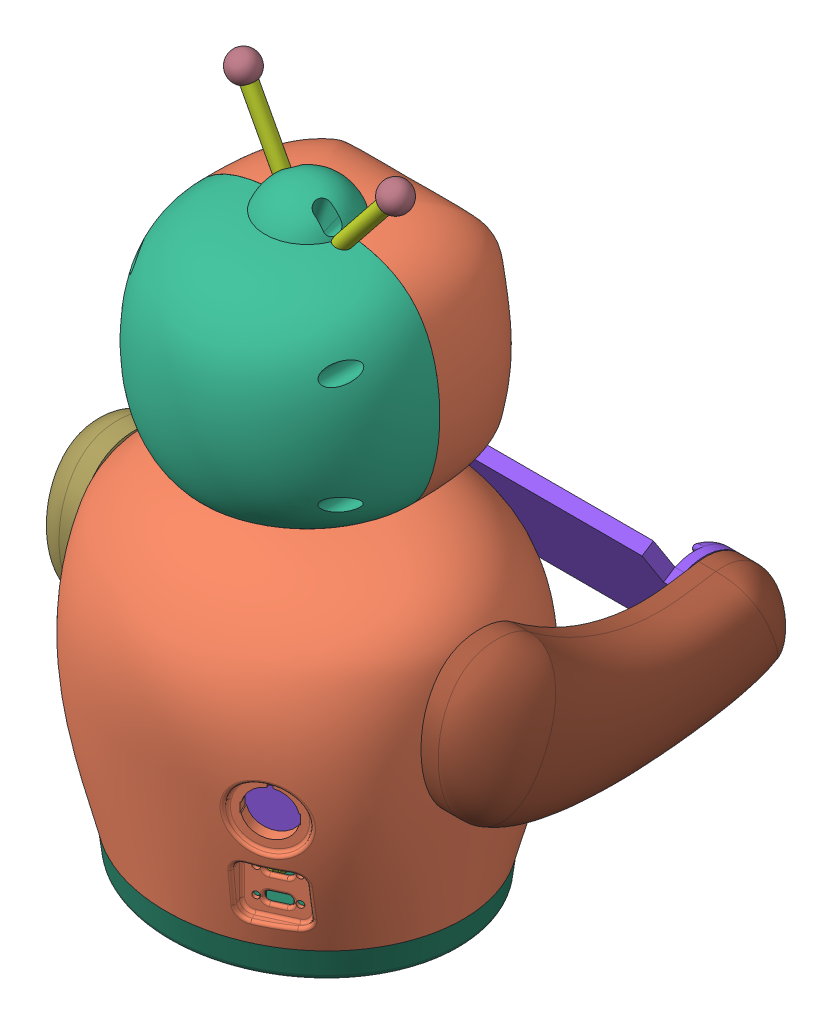
SolidWorks assembly hapi_assy, configuration Default. Lengths in mm.
Overall size (629.53 401.15 572.49).
108 component instances, 33 part files, 30 mates.
Components (placement in the parent):
- body_top_assy-1: body_top_assy [Default] at origin size (658.15 255.79 373.04)
  - body_top_with_inserts-1: body_top_with_inserts [Default] at origin size (206.75 213.33 145.9)
    - 93365A120_HEAT-SET INSERTS FOR PLASTICS-1: 93365A120_HEAT-SET INSERTS FOR PLASTICS [93365A120] at (-21.362 141.4958 103.8173) size (4.37 3.82 4.37)
    - 93365A120_HEAT-SET INSERTS FOR PLASTICS-9: 93365A120_HEAT-SET INSERTS FOR PLASTICS [93365A120] at (23.9683 141.4958 103.8173) size (4.37 3.82 4.37)
    - 93365A120_HEAT-SET INSERTS FOR PLASTICS-2: 93365A120_HEAT-SET INSERTS FOR PLASTICS [93365A120] at (-76.1668 95.7767 127.6298) x (0 1 0) z (0 0 1) size (4.37 3.82 4.37)
    - 93365A120_HEAT-SET INSERTS FOR PLASTICS-3: 93365A120_HEAT-SET INSERTS FOR PLASTICS [93365A120] at (-76.1668 75.4567 127.6298) x (0 1 0) z (0 0 1) size (4.37 3.82 4.37)
    - 93365A120_HEAT-SET INSERTS FOR PLASTICS-4: 93365A120_HEAT-SET INSERTS FOR PLASTICS [93365A120] at (-76.1668 75.4567 94.6098) x (0 1 0) z (0 0 1) size (4.37 3.82 4.37)
    - 93365A120_HEAT-SET INSERTS FOR PLASTICS-7: 93365A120_HEAT-SET INSERTS FOR PLASTICS [93365A120] at (-76.1668 95.7774 94.6098) x (0 0.999823 -0.018835) z (0 0.018835 0.999823) size (4.37 3.82 4.37)
    - 93365A120_HEAT-SET INSERTS FOR PLASTICS-5: 93365A120_HEAT-SET INSERTS FOR PLASTICS [93365A120] at (78.7732 75.4567 94.6098) x (0 -1 0) z (0 0 1) size (4.37 3.82 4.37)
    - 93365A120_HEAT-SET INSERTS FOR PLASTICS-6: 93365A120_HEAT-SET INSERTS FOR PLASTICS [93365A120] at (78.7732 95.7767 94.6098) x (0 -0.078661 -0.996901) z (0 -0.996901 0.078661) size (4.37 3.82 4.37)
    - 93365A120_HEAT-SET INSERTS FOR PLASTICS-11: 93365A120_HEAT-SET INSERTS FOR PLASTICS [93365A120] at (78.7732 95.7767 127.6298) x (0 0.381849 -0.924225) z (0 -0.924225 -0.381849) size (4.37 3.82 4.37)
    - 93365A120_HEAT-SET INSERTS FOR PLASTICS-8: 93365A120_HEAT-SET INSERTS FOR PLASTICS [93365A120] at (78.7732 75.4567 127.6298) x (0 0.381849 -0.924225) z (0 -0.924225 -0.381849) size (4.37 3.82 4.37)
    - 93365A120_HEAT-SET INSERTS FOR PLASTICS-10: 93365A120_HEAT-SET INSERTS FOR PLASTICS [93365A120] at (1.3032 4.3358 165.2218) x (-0.837169 0 -0.546944) z (-0.546944 0 0.837169) size (4.37 3.82 4.37)
    - 93365A120_HEAT-SET INSERTS FOR PLASTICS-12: 93365A120_HEAT-SET INSERTS FOR PLASTICS [93365A120] at (1.3032 4.3358 57.0178) x (-0.837169 0 -0.546944) z (-0.546944 0 0.837169) size (4.37 3.82 4.37)
    - 93365A120_HEAT-SET INSERTS FOR PLASTICS-13: 93365A120_HEAT-SET INSERTS FOR PLASTICS [93365A120] at (-59.1488 4.3358 111.1198) x (-0.837169 0 -0.546944) z (-0.546944 0 0.837169) size (4.37 3.82 4.37)
    - body_top-1: body_top [Default] at (1.3032 1.7958 111.1198) x (-1 0 0) z (0 0 1) size (162.51 139.72 145.9)
  - servomotor-1: servomotor [Predeterminado] at (61.1232 86.3965 111.1198) x (0 1 0) z (0 0 -1) size (53.82 44.84 19.95)
  - arm_base_right_assy-1: arm_base_right_assy [Default] at origin size (122.68 69.3 143.51)
    - 5862K103_HIGH-PULL RARE EARTH MAGNETIC DISC-1: 5862K103_HIGH-PULL RARE EARTH MAGNETIC DISC [5862K103] at (91.2192 74.4457 42.5401) x (0 0.971715 -0.236156) z (0 0.236156 0.971715) size (6.35 3.17 6.35)
    - 6455K130_GENERAL PURPOSE PLASTIC BALL BEARING-1: 6455K130_GENERAL PURPOSE PLASTIC BALL BEARING [6455K13] at (82.345 74.4457 9.5201) x (0 0 1) z (-1 0 0) size (19.05 19.05 7.14)
    - arm_base_right-1: arm_base_right [Default] at (78.7732 -8.1043 111.1198) x (0 0 -1) z (1 0 0) size (143.51 69.3 15.38)
    - 93365A120_HEAT-SET INSERTS FOR PLASTICS-1: 93365A120_HEAT-SET INSERTS FOR PLASTICS [93365A120] at (78.7732 61.7465 116.0548) x (0 -0.381849 0.924225) z (0 -0.924225 -0.381849) size (4.37 3.82 4.37)
    - 93365A120_HEAT-SET INSERTS FOR PLASTICS-3: 93365A120_HEAT-SET INSERTS FOR PLASTICS [93365A120] at (78.7732 61.7465 106.1848) x (0 -0.381849 0.924225) z (0 -0.924225 -0.381849) size (4.37 3.82 4.37)
    - 5862K103_HIGH-PULL RARE EARTH MAGNETIC DISC-2: 5862K103_HIGH-PULL RARE EARTH MAGNETIC DISC [5862K103] at (91.2192 74.4457 80.6401) x (0 -0.018077 -0.999837) z (0 0.999837 -0.018077) size (6.35 3.17 6.35)
  - arm_base_left_assy-1: arm_base_left_assy [Default] at origin size (53.96 69.3 143.51)
    - arm_base_left-1: arm_base_left [Default] at (-76.1668 -8.1043 111.1198) x (0 0 -1) z (1 0 0) size (143.51 69.3 15.38)
    - 6455K130_GENERAL PURPOSE PLASTIC BALL BEARING-1: 6455K130_GENERAL PURPOSE PLASTIC BALL BEARING [6455K13] at (-79.7387 74.4464 9.5201) x (0 0 1) z (-1 0 0) size (19.05 19.05 7.14)
    - 5862K103_HIGH-PULL RARE EARTH MAGNETIC DISC-1: 5862K103_HIGH-PULL RARE EARTH MAGNETIC DISC [5862K103] at (-88.6128 74.4457 42.5401) x (0 -1 0) z (0 0 1) size (6.35 3.17 6.35)
    - 5862K103_HIGH-PULL RARE EARTH MAGNETIC DISC-2: 5862K103_HIGH-PULL RARE EARTH MAGNETIC DISC [5862K103] at (-88.6128 74.4457 80.6401) x (0 0.374307 -0.927305) z (0 -0.927305 -0.374307) size (6.35 3.17 6.35)
  - phone holder-1: phone holder [Default] at (1.3032 39.7869 -9.1365) x (0 -0.540748 0.841184) z (-1 0 0) size (24.64 78.49 181.62)
  - servo_timing_belt_pulley-1: servo_timing_belt_pulley [Default] at (96.8707 76.1465 111.1198) x (0 -0.381849 0.924225) z (0 -0.924225 -0.381849) size (25.4 13.02 25.4)
  - belt-1: belt [Default] at (91.1557 74.662 9.5306) x (0 0.107943 -0.994157) z (1 0 0) size (124.05 35.66 3.17)
  - arm_cover_right_assy-1: arm_cover_right_assy [Default] at origin size (82.05 76.51 149.69)
    - arm_cover_right-1: arm_cover_right [Default] at (86.5519 -8.1043 111.1198) x (0 0 1) z (-1 0 0) size (149.69 76.51 28.63)
    - 5862K103_HIGH-PULL RARE EARTH MAGNETIC DISC-1: 5862K103_HIGH-PULL RARE EARTH MAGNETIC DISC [5862K103] at (94.3942 74.4457 80.6401) x (0 -1 0) z (0 0 1) size (6.35 3.17 6.35)
    - 5862K103_HIGH-PULL RARE EARTH MAGNETIC DISC-2: 5862K103_HIGH-PULL RARE EARTH MAGNETIC DISC [5862K103] at (94.3942 74.4457 42.5401) x (0 -1 0) z (0 0 1) size (6.35 3.17 6.35)
  - arm_cover_left_assy-1: arm_cover_left_assy [Default] at origin size (71.69 76.51 149.69)
    - arm_cover_left-1: arm_cover_left [Default] at (-83.9456 -8.1043 111.1198) x (0 0 1) z (-1 0 0) size (149.69 76.51 28.61)
    - 5862K103_HIGH-PULL RARE EARTH MAGNETIC DISC-1: 5862K103_HIGH-PULL RARE EARTH MAGNETIC DISC [5862K103] at (-91.7878 74.4457 42.5401) x (0 1 0) z (0 0 1) size (6.35 3.17 6.35)
    - 5862K103_HIGH-PULL RARE EARTH MAGNETIC DISC-2: 5862K103_HIGH-PULL RARE EARTH MAGNETIC DISC [5862K103] at (-91.7878 74.4457 80.6401) x (0 1 0) z (0 0 1) size (6.35 3.17 6.35)
  - 1254N220_MXL SERIES LIGHTWEIGHT TIMING BELT PULLEY-1: 1254N220_MXL SERIES LIGHTWEIGHT TIMING BELT PULLEY [1254N22] at (95.2895 74.4457 9.5201) x (-1 0 0) z (0 0.957317 0.289041) size (11.13 22.35 22.35)
  - 91772A110_18-8 SS PAN HEAD PHILLIPS MACHINE SCREW-11: 91772A110_18-8 SS PAN HEAD PHILLIPS MACHINE SCREW [91772A110] at (-66.6418 95.7774 94.6098) x (0 0 1) z (-1 0 0) size (5.56 5.56 14.77)
  - 91772A110_18-8 SS PAN HEAD PHILLIPS MACHINE SCREW-12: 91772A110_18-8 SS PAN HEAD PHILLIPS MACHINE SCREW [91772A110] at (-66.6418 95.7774 127.6298) x (0 0 1) z (-1 0 0) size (5.56 5.56 14.77)
  - 91772A110_18-8 SS PAN HEAD PHILLIPS MACHINE SCREW-13: 91772A110_18-8 SS PAN HEAD PHILLIPS MACHINE SCREW [91772A110] at (-66.6418 75.4574 127.6298) x (0 0 1) z (-1 0 0) size (5.56 5.56 14.77)
  - 91772A110_18-8 SS PAN HEAD PHILLIPS MACHINE SCREW-14: 91772A110_18-8 SS PAN HEAD PHILLIPS MACHINE SCREW [91772A110] at (-66.6418 75.4574 94.6098) x (0 0 1) z (-1 0 0) size (5.56 5.56 14.77)
  - 91772A110_18-8 SS PAN HEAD PHILLIPS MACHINE SCREW-1: 91772A110_18-8 SS PAN HEAD PHILLIPS MACHINE SCREW [91772A110] at (69.2482 95.7767 94.6098) x (0 -0.903134 -0.429359) z (1 0 0) size (5.56 5.56 14.77)
  - 91772A110_18-8 SS PAN HEAD PHILLIPS MACHINE SCREW-2: 91772A110_18-8 SS PAN HEAD PHILLIPS MACHINE SCREW [91772A110] at (69.2482 75.4567 127.6298) x (0 -0.93698 -0.349383) z (1 0 0) size (5.56 5.56 14.77)
  - 91772A110_18-8 SS PAN HEAD PHILLIPS MACHINE SCREW-3: 91772A110_18-8 SS PAN HEAD PHILLIPS MACHINE SCREW [91772A110] at (69.2482 75.4567 94.6098) x (0 0.057775 -0.99833) z (1 0 0) size (5.56 5.56 14.77)
  - 91772A110_18-8 SS PAN HEAD PHILLIPS MACHINE SCREW-4: 91772A110_18-8 SS PAN HEAD PHILLIPS MACHINE SCREW [91772A110] at (69.2482 95.7767 127.6298) x (0 -0.924225 -0.381849) z (1 0 0) size (5.56 5.56 14.77)
  - 91772A110_18-8 SS PAN HEAD PHILLIPS MACHINE SCREW-9: 91772A110_18-8 SS PAN HEAD PHILLIPS MACHINE SCREW [91772A110] at (84.0132 61.7465 106.1848) x (0 0 1) z (-1 0 0) size (5.56 5.56 14.77)
  - 91772A110_18-8 SS PAN HEAD PHILLIPS MACHINE SCREW-10: 91772A110_18-8 SS PAN HEAD PHILLIPS MACHINE SCREW [91772A110] at (84.0132 61.7465 116.0548) x (0 0 1) z (-1 0 0) size (5.56 5.56 14.77)
- body_bottom_assy-1: body_bottom_assy [Default] at (-9.9974 1.6233 113.0097) x (-1 0 0) z (0 -1 0) size (140.63 129.3 227.34)
  - body_bottom-1: body_bottom [Default] at (-11.3005 1.8899 -0.1725) size (140.63 129.3 15.3)
  - 93365A120_HEAT-SET INSERTS FOR PLASTICS-1: 93365A120_HEAT-SET INSERTS FOR PLASTICS [93365A120] at (26.7995 -36.2961 -2.7125) x (-0.923728 -0.383049 0) z (0.383049 -0.923728 0) size (4.37 3.82 4.37)
  - 93365A120_HEAT-SET INSERTS FOR PLASTICS-2: 93365A120_HEAT-SET INSERTS FOR PLASTICS [93365A120] at (26.7995 21.7039 -2.7125) x (-0.923728 -0.383049 0) z (0.383049 -0.923728 0) size (4.37 3.82 4.37)
  - 93365A120_HEAT-SET INSERTS FOR PLASTICS-3: 93365A120_HEAT-SET INSERTS FOR PLASTICS [93365A120] at (-22.2005 -36.2961 -2.7125) x (-0.414944 -0.909847 0) z (0.909847 -0.414944 0) size (4.37 3.82 4.37)
  - 93365A120_HEAT-SET INSERTS FOR PLASTICS-4: 93365A120_HEAT-SET INSERTS FOR PLASTICS [93365A120] at (-22.2005 21.7039 -2.7125) x (-0.923728 -0.383049 0) z (0.383049 -0.923728 0) size (4.37 3.82 4.37)
  - rasberry_pi_4-1: rasberry_pi_4 [Default] at (-25.7005 45.2039 -2.7125) x (1 0 0) z (0 1 0) size (56 17.85 87.1)
  - PCB-1: PCB [Default] at (30.2995 -39.7961 -15.4252) x (-1 0 0) z (0 -1 0) size (56 1.6 65)
  - 90176A114_NYLON UNTHREADED SPACERS-1: 90176A114_NYLON UNTHREADED SPACERS [90176A114] at (-22.2005 21.7039 -9.869) size (4.76 4.76 11.11)
  - 90176A114_NYLON UNTHREADED SPACERS-2: 90176A114_NYLON UNTHREADED SPACERS [90176A114] at (-22.2005 -36.2961 -9.869) size (4.76 4.76 11.11)
  - 90176A114_NYLON UNTHREADED SPACERS-3: 90176A114_NYLON UNTHREADED SPACERS [90176A114] at (26.7995 21.7039 -9.869) size (4.76 4.76 11.11)
  - 90176A114_NYLON UNTHREADED SPACERS-4: 90176A114_NYLON UNTHREADED SPACERS [90176A114] at (26.7995 -36.2961 -9.869) size (4.76 4.76 11.11)
  - 91772A113_18-8 SS PAN HEAD PHILLIPS MACHINE SCREW-1: 91772A113_18-8 SS PAN HEAD PHILLIPS MACHINE SCREW [91772A113] at (26.7995 21.7039 2.0246) x (-0.748633 0.662984 0) z (0 0 -1) size (5.56 5.56 21.13)
  - 91772A113_18-8 SS PAN HEAD PHILLIPS MACHINE SCREW-2: 91772A113_18-8 SS PAN HEAD PHILLIPS MACHINE SCREW [91772A113] at (-22.2005 21.7039 2.0246) x (-0.916991 -0.398908 0) z (0 0 -1) size (5.56 5.56 21.13)
  - 91772A113_18-8 SS PAN HEAD PHILLIPS MACHINE SCREW-3: 91772A113_18-8 SS PAN HEAD PHILLIPS MACHINE SCREW [91772A113] at (26.7995 -36.2961 2.0246) x (-0.930935 -0.365185 0) z (0 0 -1) size (5.56 5.56 21.13)
  - 91772A113_18-8 SS PAN HEAD PHILLIPS MACHINE SCREW-4: 91772A113_18-8 SS PAN HEAD PHILLIPS MACHINE SCREW [91772A113] at (-22.2005 -36.2961 2.0246) x (-0.829679 -0.55824 0) z (0 0 -1) size (5.56 5.56 21.13)
- head_front_assy-1: head_front_assy [Default] at (13.1279 224.194 104.8323) x (1 0 0) z (0 0 -1) size (119.11 101.66 360.45)
  - head_front-1: head_front [Default] at (-11.8247 82.6982 -6.2875) size (119.11 101.66 54.73)
  - 91772A506_PASSIVATED 18-8 SS PAN HEAD PHILLIPS SCREW-1: 91772A506_PASSIVATED 18-8 SS PAN HEAD PHILLIPS SCREW [91772A506] at (-40.9077 7.2602 41.1788) x (-0.923728 -0.383049 0) z (0 0 -1) size (4.24 4.24 10.34)
  - 91772A506_PASSIVATED 18-8 SS PAN HEAD PHILLIPS SCREW-2: 91772A506_PASSIVATED 18-8 SS PAN HEAD PHILLIPS SCREW [91772A506] at (17.2583 56.5362 41.1788) x (-0.923728 -0.383049 0) z (0 0 -1) size (4.24 4.24 10.34)
  - 91772A506_PASSIVATED 18-8 SS PAN HEAD PHILLIPS SCREW-3: 91772A506_PASSIVATED 18-8 SS PAN HEAD PHILLIPS SCREW [91772A506] at (-40.9077 56.5362 41.1788) x (-0.923728 -0.383049 0) z (0 0 -1) size (4.24 4.24 10.34)
  - 91772A506_PASSIVATED 18-8 SS PAN HEAD PHILLIPS SCREW-4: 91772A506_PASSIVATED 18-8 SS PAN HEAD PHILLIPS SCREW [91772A506] at (17.2583 7.2602 41.1788) x (-0.923728 -0.383049 0) z (0 0 -1) size (4.24 4.24 10.34)
  - 93365A110_HEAT-SET INSERTS FOR PLASTICS-1: 93365A110_HEAT-SET INSERTS FOR PLASTICS [Default] at (17.2583 56.5362 35.6225) x (1 0 0) z (0 1 0) size (3.58 3.09 3.58)
  - 93365A110_HEAT-SET INSERTS FOR PLASTICS-2: 93365A110_HEAT-SET INSERTS FOR PLASTICS [Default] at (-40.9077 56.5362 35.6225) x (-0.923728 -0.383049 0) z (0.383049 -0.923728 0) size (3.58 3.09 3.58)
  - 93365A110_HEAT-SET INSERTS FOR PLASTICS-3: 93365A110_HEAT-SET INSERTS FOR PLASTICS [Default] at (17.2583 7.2602 35.6225) x (-0.923728 -0.383049 0) z (0.383049 -0.923728 0) size (3.58 3.09 3.58)
  - 93365A110_HEAT-SET INSERTS FOR PLASTICS-4: 93365A110_HEAT-SET INSERTS FOR PLASTICS [Default] at (-40.9077 7.2602 35.6225) x (-0.923728 -0.383049 0) z (0.383049 -0.923728 0) size (3.58 3.09 3.58)
  - led_screen-1: led_screen [Default] at (-11.8247 -16.6793 -15.1775) size (65.02 56.51 3.17)
  - 93365A120_HEAT-SET INSERTS FOR PLASTICS-1: 93365A120_HEAT-SET INSERTS FOR PLASTICS [93365A120] at (33.8953 57.2982 -3.7475) x (1 0 0) z (0 1 0) size (4.37 3.82 4.37)
  - 93365A120_HEAT-SET INSERTS FOR PLASTICS-2: 93365A120_HEAT-SET INSERTS FOR PLASTICS [93365A120] at (-57.5447 6.4982 -3.7475) x (-0.923728 -0.383049 0) z (0.383049 -0.923728 0) size (4.37 3.82 4.37)
  - 93365A120_HEAT-SET INSERTS FOR PLASTICS-3: 93365A120_HEAT-SET INSERTS FOR PLASTICS [93365A120] at (33.8953 6.4982 -3.7475) x (1 0 0) z (0 1 0) size (4.37 3.82 4.37)
  - 93365A120_HEAT-SET INSERTS FOR PLASTICS-4: 93365A120_HEAT-SET INSERTS FOR PLASTICS [93365A120] at (-57.5447 57.2982 -3.7475) x (1 0 0) z (0 1 0) size (4.37 3.82 4.37)
- head_back_assy-1: head_back_assy [Default] at (13.1279 224.194 104.8323) x (1 0 0) z (0 0 -1) size (119.16 148.35 78.63)
  - head_back-1: head_back [Default] at (-11.8247 82.6982 -6.2875) size (119.16 114.31 78.63)
  - antenna_bottom-1: antenna_bottom [Default] at (-7.1516 0.8703 -10.9865) x (0.624558 -0.780979 0) z (0 0 -1) size (79.11 16.26 6.35)
  - antenna_bottom-2: antenna_bottom [Default] at (-15.3499 0.114 -1.5885) x (-0.471145 -0.882056 0) z (0 0 -1) size (79.11 16.26 6.35)
  - dc_motor-1: dc_motor [Default] at (-17.8572 45.0427 -36.3611) x (1 0 0) z (0 -1 0) size (12.06 35.51 10.03)
  - crank-1: crank [Default] at (-11.8247 40.0262 -9.4625) x (0.420949 -0.907084 0) z (-0.907084 -0.420949 0) size (42.45 8.16 55.15)
  - 98002A709_STEEL BINDING SCREWS-1: 98002A709_STEEL BINDING SCREWS [98002A709] at (-11.8247 6.7138 -14.225) x (0 0 -1) z (0 1 0) size (11.33 11.11 11.11)
  - 99637A212_18-8 STAINLESS STEEL BINDING BARREL-1: 99637A212_18-8 STAINLESS STEEL BINDING BARREL [99637A212] at (-11.8247 6.7138 -28.5125) x (0 0 -1) z (-0.187402 -0.982283 0) size (35.2 11.11 11.11)
  - antenna fixture-1: antenna fixture [Default] at (-11.8247 16.8738 -21.9085) x (-1 0 0) z (0 1 0) size (35.24 32.7 28.83)
  - antenna_top-1: antenna_top [Default] at (32.5078 -48.7218 -10.9865) x (-0.139984 -0.111947 -0.983805) z (-0.624558 0.780979 0) size (12.7 12.7 11.69)
  - antenna_top-2: antenna_top [Default] at (-45.2677 -55.8965 -1.5885) x (-0.735434 0.392828 -0.552108) z (0.471145 0.882056 0) size (12.7 12.7 11.69)
  - 98381A325_DOWEL PIN-1: 98381A325_DOWEL PIN [98381A325] at (-0.3947 7.1332 3.8725) x (0 1 0) z (0.158679 0 0.98733) size (54.61 4.76 4.76)
  - 98381A325_DOWEL PIN-2: 98381A325_DOWEL PIN [98381A325] at (-23.2547 7.1332 -16.4475) x (0 1 0) z (-0.401809 0 0.915724) size (54.61 4.76 4.76)
  - 98381A539_ALLOY STEEL DOWEL PIN-1: 98381A539_ALLOY STEEL DOWEL PIN [98381A539] at (-15.3172 22.5888 3.5392) x (-1 0 0) z (0 -0.095607 0.995419) size (15.88 6.35 6.35)
  - 98381A539_ALLOY STEEL DOWEL PIN-2: 98381A539_ALLOY STEEL DOWEL PIN [98381A539] at (-8.3322 22.5888 -16.2411) size (15.88 6.35 6.35)
  - 93365A120_HEAT-SET INSERTS FOR PLASTICS-1: 93365A120_HEAT-SET INSERTS FOR PLASTICS [93365A120] at (-11.8247 49.0432 -26.1249) size (4.37 3.82 4.37)
  - 91772A110_18-8 SS PAN HEAD PHILLIPS MACHINE SCREW-1: 91772A110_18-8 SS PAN HEAD PHILLIPS MACHINE SCREW [91772A110] at (-11.8247 45.0427 -26.1249) x (1 0 0) z (0 1 0) size (5.56 5.56 14.77)
- 91772A110_18-8 SS PAN HEAD PHILLIPS MACHINE SCREW-6: 91772A110_18-8 SS PAN HEAD PHILLIPS MACHINE SCREW [91772A110] at (-44.4168 217.6958 98.4198) x (0.683884 0.729591 0) z (0 0 1) size (5.56 5.56 14.77)
- 91772A110_18-8 SS PAN HEAD PHILLIPS MACHINE SCREW-5: 91772A110_18-8 SS PAN HEAD PHILLIPS MACHINE SCREW [91772A110] at (47.0232 166.8958 98.4198) x (-0.903403 0.428793 0) z (0 0 1) size (5.56 5.56 14.77)
- 91772A110_18-8 SS PAN HEAD PHILLIPS MACHINE SCREW-4: 91772A110_18-8 SS PAN HEAD PHILLIPS MACHINE SCREW [91772A110] at (47.0232 217.6958 98.4198) x (-0.683884 -0.729591 0) z (0 0 1) size (5.56 5.56 14.77)
- 91772A110_18-8 SS PAN HEAD PHILLIPS MACHINE SCREW-3: 91772A110_18-8 SS PAN HEAD PHILLIPS MACHINE SCREW [91772A110] at (-44.4168 166.8958 98.4198) x (-0.683884 -0.729591 0) z (0 0 1) size (5.56 5.56 14.77)
- 91772A110_18-8 SS PAN HEAD PHILLIPS MACHINE SCREW-7: 91772A110_18-8 SS PAN HEAD PHILLIPS MACHINE SCREW [91772A110] at (1.3032 14.4958 165.2218) x (0.581774 0 -0.81335) z (0 -1 0) size (5.56 5.56 14.77)
- 91772A110_18-8 SS PAN HEAD PHILLIPS MACHINE SCREW-8: 91772A110_18-8 SS PAN HEAD PHILLIPS MACHINE SCREW [91772A110] at (1.3032 14.4958 57.0178) x (0.581774 0 -0.81335) z (0 -1 0) size (5.56 5.56 14.77)
- 91772A110_18-8 SS PAN HEAD PHILLIPS MACHINE SCREW-9: 91772A110_18-8 SS PAN HEAD PHILLIPS MACHINE SCREW [91772A110] at (-59.1488 14.4958 111.1198) x (0.749197 0 -0.662348) z (0 -1 0) size (5.56 5.56 14.77)
- 91772A110_18-8 SS PAN HEAD PHILLIPS MACHINE SCREW-1: 91772A110_18-8 SS PAN HEAD PHILLIPS MACHINE SCREW [91772A110] at (-21.362 133.8758 103.8173) x (-0.815451 0 -0.578826) z (0 1 0) size (5.56 5.56 14.77)
- 91772A110_18-8 SS PAN HEAD PHILLIPS MACHINE SCREW-2: 91772A110_18-8 SS PAN HEAD PHILLIPS MACHINE SCREW [91772A110] at (23.9683 133.8758 103.8173) x (0.370897 0 -0.928674) z (0 1 0) size (5.56 5.56 14.77)
Mates (geometry in assembly coordinates):
- Coincident92: coincident anti-aligned: plane of head_front_assy-1/head_front-1 through (1.3032 146.5758 111.1198) normal (0 1 0); plane of 91772A110_18-8 SS PAN HEAD PHILLIPS MACHINE SCREW-2 through (23.9683 146.5758 103.8173) normal (0 -1 0)
- Coincident93: coincident anti-aligned: plane of head_front_assy-1/head_front-1 through (1.3032 146.5758 111.1198) normal (0 1 0); plane of 91772A110_18-8 SS PAN HEAD PHILLIPS MACHINE SCREW-1 through (-21.362 146.5758 103.8173) normal (0 -1 0)
- Concentric62: concentric aligned: cylinder of head_front_assy-1/head_front-1 through (23.9683 146.5758 103.8173) axis (0 1 0) radius 1.5875; circle of 91772A110_18-8 SS PAN HEAD PHILLIPS MACHINE SCREW-2
- Concentric63: concentric aligned: cylinder of head_front_assy-1/head_front-1 through (-21.362 146.5758 103.8173) axis (0 1 0) radius 1.5875; circle of 91772A110_18-8 SS PAN HEAD PHILLIPS MACHINE SCREW-1
- Coincident95: coincident anti-aligned: plane of head_back_assy-1/head_back-1 through (55.6764 196.2378 108.5798) normal (0 0 -1); plane of head_front_assy-1/head_front-1 through (-55.8329 196.9465 108.5798) normal (0 0 1)
- Coincident96: coincident aligned: plane of head_back_assy-1/head_back-1 through (1.3032 141.4958 111.1198) normal (0 -1 0); plane of head_front_assy-1/head_front-1 through (1.3032 141.4958 111.1198) normal (0 -1 0)
- Coincident97: coincident aligned: plane of head_back_assy-1/head_back-1 through (1.3032 141.4958 111.1198) normal (1 0 0); plane of head_front_assy-1/head_front-1 through (1.3032 141.4958 111.1198) normal (1 0 0)
- Concentric64: concentric anti-aligned: circle of head_back_assy-1/head_back-1; circle of 91772A110_18-8 SS PAN HEAD PHILLIPS MACHINE SCREW-3
- Coincident98: coincident anti-aligned: plane of head_back_assy-1/head_back-1 through (-44.4168 166.8958 111.1198) normal (0 0 1); plane of 91772A110_18-8 SS PAN HEAD PHILLIPS MACHINE SCREW-3 through (-44.4168 166.8958 111.1198) normal (0 0 -1)
- Concentric65: concentric anti-aligned: circle of head_back_assy-1/head_back-1; circle of 91772A110_18-8 SS PAN HEAD PHILLIPS MACHINE SCREW-4
- Coincident99: coincident anti-aligned: plane of head_back_assy-1/head_back-1 through (47.0232 217.6958 111.1198) normal (0 0 1); plane of 91772A110_18-8 SS PAN HEAD PHILLIPS MACHINE SCREW-4 through (47.0232 217.6958 111.1198) normal (0 0 -1)
- Concentric66: concentric aligned: circle of head_back_assy-1/head_back-1; circle of 91772A110_18-8 SS PAN HEAD PHILLIPS MACHINE SCREW-5
- Coincident100: coincident anti-aligned: plane of head_back_assy-1/head_back-1 through (47.0232 166.8958 111.1198) normal (0 0 1); plane of 91772A110_18-8 SS PAN HEAD PHILLIPS MACHINE SCREW-5 through (47.0232 166.8958 111.1198) normal (0 0 -1)
- Concentric67: concentric aligned: circle of head_back_assy-1/head_back-1; circle of 91772A110_18-8 SS PAN HEAD PHILLIPS MACHINE SCREW-6
- Coincident101: coincident anti-aligned: plane of head_back_assy-1/head_back-1 through (-44.4168 217.6958 111.1198) normal (0 0 1); plane of 91772A110_18-8 SS PAN HEAD PHILLIPS MACHINE SCREW-6 through (-44.4168 217.6958 111.1198) normal (0 0 -1)
- Coincident102: coincident anti-aligned: plane of 91772A110_18-8 SS PAN HEAD PHILLIPS MACHINE SCREW-7 through (1.3032 1.7958 165.2218) normal (0 1 0); plane of body_bottom_assy-1/body_bottom_4-1 through (-25.2593 1.7958 55.421) normal (0 -1 0)
- Concentric71: concentric aligned: circle of 91772A110_18-8 SS PAN HEAD PHILLIPS MACHINE SCREW-7; circle of body_bottom_assy-1/body_bottom_4-1
- Coincident103: coincident anti-aligned: plane of 91772A110_18-8 SS PAN HEAD PHILLIPS MACHINE SCREW-8 through (1.3032 1.7958 57.0178) normal (0 1 0); plane of body_bottom_assy-1/body_bottom_4-1 through (-25.2593 1.7958 55.421) normal (0 -1 0)
- Concentric72: concentric aligned: circle of 91772A110_18-8 SS PAN HEAD PHILLIPS MACHINE SCREW-8; circle of body_bottom_assy-1/body_bottom_4-1
- Coincident104: coincident anti-aligned: plane of 91772A110_18-8 SS PAN HEAD PHILLIPS MACHINE SCREW-9 through (-59.1488 1.7958 111.1198) normal (0 1 0); plane of body_bottom_assy-1/body_bottom_4-1 through (-25.2593 1.7958 55.421) normal (0 -1 0)
- Concentric73: concentric aligned: circle of 91772A110_18-8 SS PAN HEAD PHILLIPS MACHINE SCREW-9; circle of body_bottom_assy-1/body_bottom_4-1
- Coincident105: coincident anti-aligned: plane of body_top_assy-1/body_top_with_inserts-1/body_top-1 through (1.3032 141.4958 111.1198) normal (0 1 0); plane of head_front_assy-1/head_front-1 through (1.3032 141.4958 111.1198) normal (0 -1 0)
- Concentric74: concentric anti-aligned: circle of body_top_assy-1/body_top_with_inserts-1/93365A120_HEAT-SET INSERTS FOR PLASTICS-9; circle of 91772A110_18-8 SS PAN HEAD PHILLIPS MACHINE SCREW-2
- Concentric75: concentric anti-aligned: circle of body_top_assy-1/body_top_with_inserts-1/93365A120_HEAT-SET INSERTS FOR PLASTICS-1; circle of 91772A110_18-8 SS PAN HEAD PHILLIPS MACHINE SCREW-1
- Concentric76: concentric anti-aligned: circle of 91772A110_18-8 SS PAN HEAD PHILLIPS MACHINE SCREW-8; circle of body_top_assy-1/body_top_with_inserts-1/93365A120_HEAT-SET INSERTS FOR PLASTICS-12
- Concentric77: concentric anti-aligned: circle of 91772A110_18-8 SS PAN HEAD PHILLIPS MACHINE SCREW-9; circle of body_top_assy-1/body_top_with_inserts-1/93365A120_HEAT-SET INSERTS FOR PLASTICS-13
- Coincident107: coincident anti-aligned: plane of body_top_assy-1/body_top_with_inserts-1/body_top-1 through (-66.2607 4.3358 111.232) normal (0 -1 0); plane of body_bottom_assy-1/body_bottom_4-1 through (-25.2593 4.3358 55.421) normal (0 1 0)
- Coincident108: coincident aligned: plane of body_top_assy-1 through (0 0 0) normal (0 1 0); plane of assembly through (0 0 0) normal (0 1 0)
- Coincident109: coincident aligned: plane of body_top_assy-1 through (0 0 0) normal (1 0 0); plane of assembly through (0 0 0) normal (1 0 0)
- Coincident110: coincident aligned: plane of body_top_assy-1 through (0 0 0) normal (0 0 1); plane of assembly through (0 0 0) normal (0 0 1)
